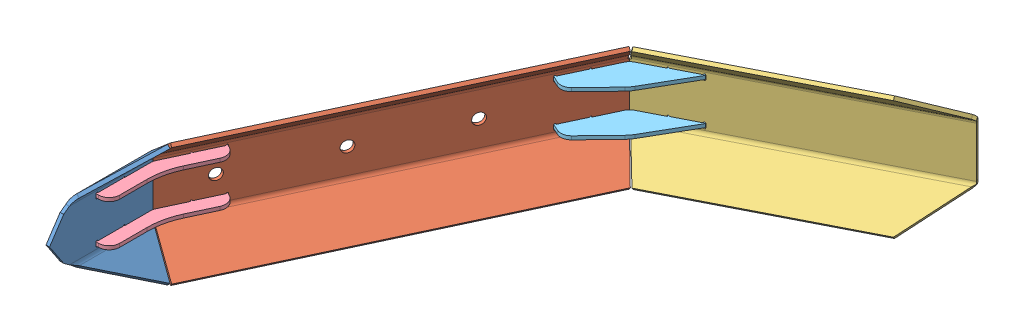
SolidWorks assembly WeldedSidePanel, configuration Default. Lengths in mm.
Overall size (379.85 111 492.63).
7 component instances, 5 part files, 18 mates.
Components (placement in the parent):
- SideArmorPart1-1: SideArmorPart1 [Default] at (-26.5814 48.0848 125.9668) size (33.2 109.47 92.87)
- SideArmorPart2-1: SideArmorPart2 [Default] at (40.639 48.0848 -65.9452) x (0.906308 0 0.422618) z (0.422618 0 -0.906308) size (36.8 111 321.87)
- SideArmorPart3-1: SideArmorPart3 [Default] at (215.1422 48.0848 -268.5972) x (0.45399 0 0.891007) z (0.891007 0 -0.45399) size (36.8 111 231.78)
- 25degSideArmorGusset-1: 25degSideArmorGusset [Default] at (-23.4064 27.7648 78.9133) x (-0.422618 0 0.906308) z (-0.906308 0 -0.422618) size (97.85 3.18 31.08)
- 38degSideArmorGusset-1: 38degSideArmorGusset [Default] at (112.6199 27.7648 -212.7961) x (-0.891007 0 0.45399) z (-0.45399 0 -0.891007) size (92.3 3.18 41.97)
- 25degSideArmorGusset-2: 25degSideArmorGusset [Default] at (-23.4064 65.2298 78.9133) x (-0.422618 0 0.906308) z (-0.906308 0 -0.422618) size (97.85 3.18 31.08)
- 38degSideArmorGusset-2: 38degSideArmorGusset [Default] at (112.6199 65.2298 -212.7961) x (-0.891007 0 0.45399) z (-0.45399 0 -0.891007) size (92.3 3.18 41.97)
Mates (geometry in assembly coordinates):
- Coincident1: coincident aligned: line of SideArmorPart1-1 through (-23.4064 25.8598 78.9133) axis (0 1 0); line of SideArmorPart2-1 through (-23.4064 25.8598 78.9133) axis (0 1 0)
- Coincident2: coincident: moEndPointRef_w of SideArmorPart1-1; moEndPointRef_w of SideArmorPart2-1
- Coincident3: coincident aligned: line of SideArmorPart2-1 through (112.6199 25.8598 -212.7961) axis (0 1 0); line of SideArmorPart3-1 through (112.6199 25.8598 -212.7961) axis (0 1 0)
- Coincident4: coincident: moEndPointRef_w of SideArmorPart2-1; moEndPointRef_w of SideArmorPart3-1
- Angle1: planar angle = 0.436332 rad aligned: plane of SideArmorPart1-1 through (-23.4064 48.0848 125.9668) normal (1 0 0); plane of SideArmorPart2-1 through (43.5165 48.0848 -64.6034) normal (0.906308 0 0.422618)
- Angle2: planar angle = 0.663225 rad aligned: plane of SideArmorPart2-1 through (43.5165 48.0848 -64.6034) normal (0.906308 0 0.422618); plane of SideArmorPart3-1 through (216.5836 48.0848 -265.7682) normal (0.45399 0 0.891007)
- Coincident7: coincident aligned: plane of 25degSideArmorGusset-1 through (-23.4064 30.9398 78.9133) normal (-1 0 0); plane of 25degSideArmorGusset-2 through (-23.4064 68.4048 78.9133) normal (-1 0 0)
- Coincident8: coincident aligned: plane of 25degSideArmorGusset-1 through (-1.9374 30.9398 32.8728) normal (-0.906308 0 -0.422618); plane of 25degSideArmorGusset-2 through (-1.9374 68.4048 32.8728) normal (-0.906308 0 -0.422618)
- Coincident9: coincident aligned: plane of 38degSideArmorGusset-1 through (157.883 30.9398 -235.8588) normal (-0.45399 0 -0.891007); plane of 38degSideArmorGusset-2 through (157.883 68.4048 -235.8588) normal (-0.45399 0 -0.891007)
- Coincident10: coincident aligned: plane of 38degSideArmorGusset-1 through (112.6199 30.9398 -212.7961) normal (-0.906308 0 -0.422618); plane of 38degSideArmorGusset-2 through (112.6199 68.4048 -212.7961) normal (-0.906308 0 -0.422618)
- Coincident11: coincident anti-aligned: plane of SideArmorPart2-1 through (43.5165 48.0848 -64.6034) normal (0.906308 0 0.422618); plane of 25degSideArmorGusset-1 through (-1.9374 30.9398 32.8728) normal (-0.906308 0 -0.422618)
- Distance2: distance = 17.145 mm: moEndPointRef_w of SideArmorPart1-1; plane of 25degSideArmorGusset-2 through (-23.4064 65.2298 78.9133) normal (0 -1 0)
- Distance3: distance = 17.145 mm: moEndPointRef_w of SideArmorPart1-1; plane of 25degSideArmorGusset-1 through (-23.4064 30.9398 78.9133) normal (0 1 0)
- Coincident18: coincident: plane of SideArmorPart1-1 through (-23.4064 48.0848 125.9668) normal (1 0 0); line of 25degSideArmorGusset-2 through (-23.4064 68.4048 81.0249) axis (0 -1 0)
- Coincident19: coincident anti-aligned: plane of SideArmorPart2-1 through (43.5165 48.0848 -64.6034) normal (0.906308 0 0.422618); plane of 38degSideArmorGusset-2 through (112.6199 68.4048 -212.7961) normal (-0.906308 0 -0.422618)
- Coincident20: coincident aligned: plane of 25degSideArmorGusset-2 through (-23.4064 68.4048 78.9133) normal (0 1 0); plane of 38degSideArmorGusset-2 through (112.6199 68.4048 -212.7961) normal (0 1 0)
- Coincident21: coincident aligned: plane of 25degSideArmorGusset-1 through (-23.4064 30.9398 78.9133) normal (0 1 0); plane of 38degSideArmorGusset-1 through (112.6199 30.9398 -212.7961) normal (0 1 0)
- Coincident22: coincident: plane of SideArmorPart3-1 through (216.5836 48.0848 -265.7682) normal (0.45399 0 0.891007); line of 38degSideArmorGusset-2 through (135.2514 65.2298 -224.3274) axis (0 1 0)
